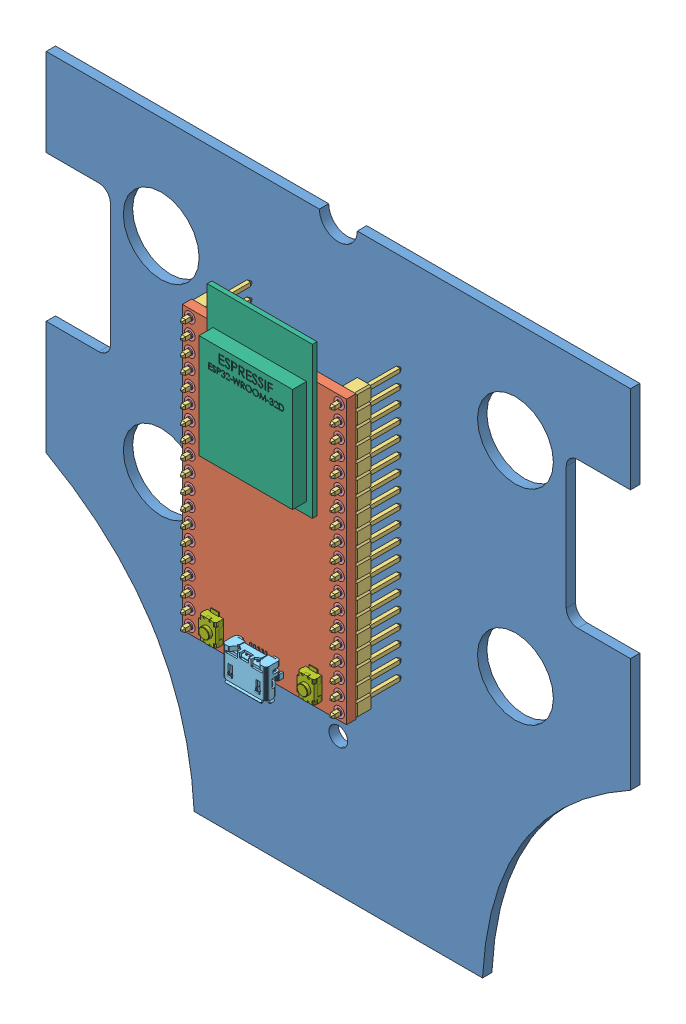
SolidWorks assembly PCB_assembly, configuration 默认. Lengths in mm.
Overall size (100 100 17.98).
10 component instances, 7 part files, 3 mates.
Components (placement in the parent):
- PCB-1: PCB [默认] at (-57.54 22.7378 -0.8) size (100 100 1.6)
- ESP32-WROOM-32D-1: ESP32-WROOM-32D [默认] at (-57.54 20.4078 11.84) x (1 0 0) z (0 -1 0) size (28.1 14.23 54.86)
  - Main-PCB.STEP-1: Main-PCB.STEP [默认] x (1 0 0) z (0 1 0) size (28.1 48.26 1.6)
  - zl201-19_p2-54_l48-3_w2-54_h8-9.STEP-1: zl201-19_p2-54_l48-3_w2-54_h8-9.STEP [默认] at (-12.78 -0.25 22.86) x (0 0 1) z (0 -1 0) size (48.26 2.54 11.94)
  - zl201-19_p2-54_l48-3_w2-54_h8-9.STEP-2: zl201-19_p2-54_l48-3_w2-54_h8-9.STEP [默认] at (12.78 -0.25 -22.86) x (0 0 -1) z (0 -1 0) size (48.26 2.54 11.94)
  - Soldering-Contacts.STEP-1: Soldering-Contacts.STEP [默认] at (0 1.6 0) x (1 0 0) z (0 1 0) size (27.34 47.52 2)
  - ab2_usb_micro_smd.wrl.STEP-1: ab2_usb_micro_smd.wrl.STEP [默认] at (0 2.585 24.73) x (1 0 0) z (0 1 0) size (8 5.6 3.57)
  - ESP32-chip.STEP-1: ESP32-chip.STEP [默认] at (0 1.6 0) x (1 0 0) z (0 1 0) size (18 25.8 3.2)
  - 3x4x2mm_tact_button.STEP-1: 3x4x2mm_tact_button.STEP [默认] at (9.1347 1.6 18.3459) x (0 0 1) z (-1 0 0) size (5 2 2.9)
  - 3x4x2mm_tact_button.STEP-2: 3x4x2mm_tact_button.STEP [默认] at (-7.7053 1.6 18.3459) x (0 0 1) z (-1 0 0) size (5 2 2.9)
Mates (geometry in assembly coordinates):
- 距离1: distance = 8.5 mm anti-aligned: plane of ESP32-WROOM-32D-1/zl201-19_p2-54_l48-3_w2-54_h8-9.STEP-1 through (-70.32 0.0878 9.3) normal (0 0 -1); plane of PCB-1 through (-89.2369 -18.5148 0.8) normal (0 0 1)
- 距离2: distance = 7.2 mm aligned: plane of ESP32-WROOM-32D-1/ESP32-chip.STEP-1 through (-66.54 50.5378 14.24) normal (0 1 0); plane of PCB-1 through (-107.54 57.7378 0.8) normal (0 1 0)
- 距离3: distance = 24.95 mm aligned: plane of PCB-1 through (-96.54 40.7378 0.8) normal (-1 0 0); plane of ESP32-WROOM-32D-1/zl201-19_p2-54_l48-3_w2-54_h8-9.STEP-1 through (-71.59 29.0478 9.3) normal (-1 0 0)
